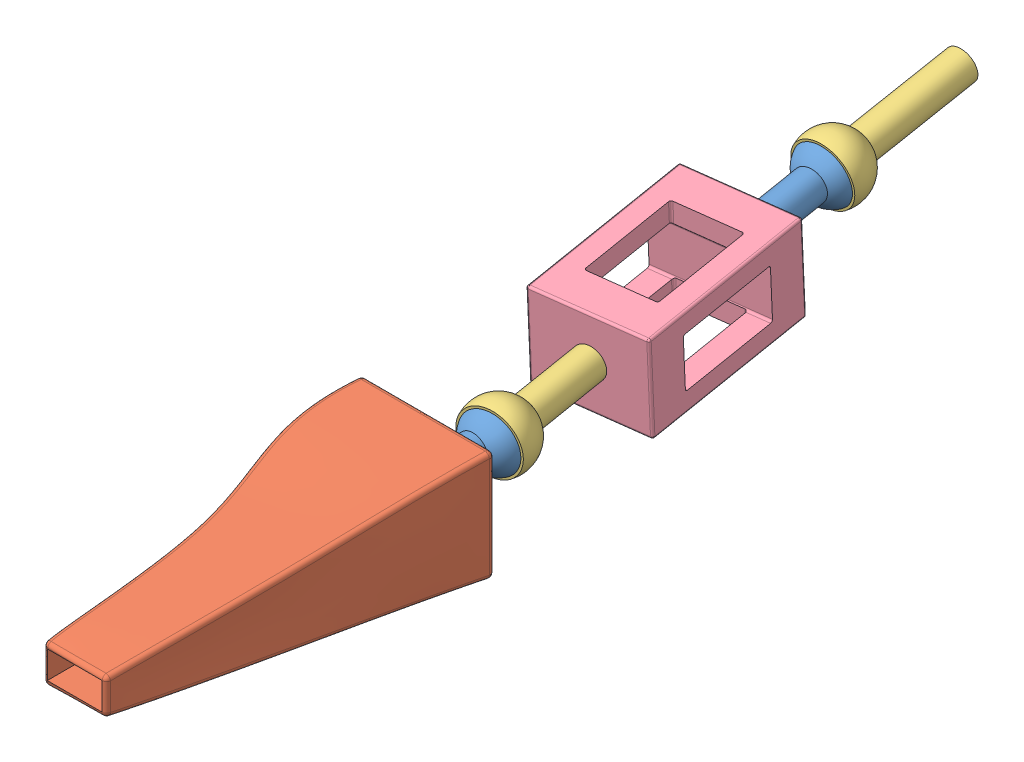
SolidWorks assembly Assem5, configuration Default. Lengths in mm.
Overall size (75.07 61 428.25).
7 component instances, 4 part files, 5 mates.
Components (placement in the parent):
- Forearm with joint-1: Forearm with joint [Default] at (-7.6339 87.1213 145.9773) size (68.05 50 255.84)
  - ball joint 11-1: ball joint 11 [Default] at (46.4533 44.5409 31.6591) size (26.96 26.96 75)
  - Part new 1-1: Part new 1 [Default] at (46.4533 44.5409 51.6591) size (68.05 50 160.01)
  - Part14-1: Part14 [Default] at (48.0088 43.9559 32.6216) x (0.992304 -0.002918 -0.123792) z (0.123524 -0.046452 0.991254) size (28.81 28.81 67)
- upper-1: upper [Default] at (23.0815 137.5806 39.8233) x (0.992337 0.002882 -0.123524) z (0.123524 -0.046452 0.991254) size (50 40 80)
- ball joint 11-1: ball joint 11 [Default] at (18.7581 139.2064 5.1294) x (0.992337 0.002882 -0.123524) z (0.123524 -0.046452 0.991254) size (26.96 26.96 75)
- Part14-1: Part14 [Default] at (18.0177 138.1852 6.1876) x (0.675646 -0.726112 -0.127529) z (0.054206 -0.123588 0.990852) size (28.81 28.81 67)
Mates (geometry in assembly coordinates):
- Coincident2: coincident: plane of Forearm with joint-1/Part14-1 through (31.1105 134.5612 104.2548) normal (-0.123524 0.046452 -0.991254); plane of upper-1 through (31.1105 134.5612 104.2548) normal (0.123524 -0.046452 0.991254)
- Concentric1: concentric: cylinder of Forearm with joint-1/Part14-1 through (31.1105 134.5612 104.2548) axis (0.123524 -0.046452 0.991254) radius 7; cylinder of upper-1 through (31.1105 134.5612 104.2548) axis (0.123524 -0.046452 0.991254) radius 7
- Concentric2: concentric: sphere of ball joint 11-1; sphere of Part14-1
- Concentric3: concentric: cylinder of upper-1 through (24.9343 136.8838 54.6921) axis (-0.123524 0.046452 -0.991254) radius 7; cylinder of ball joint 11-1 through (24.9343 136.8838 54.6921) axis (-0.123524 0.046452 -0.991254) radius 7
- Coincident3: coincident: plane of upper-1 through (24.9343 136.8838 54.6921) normal (-0.123524 0.046452 -0.991254); plane of ball joint 11-1 through (24.9343 136.8838 54.6921) normal (0.123524 -0.046452 0.991254)
